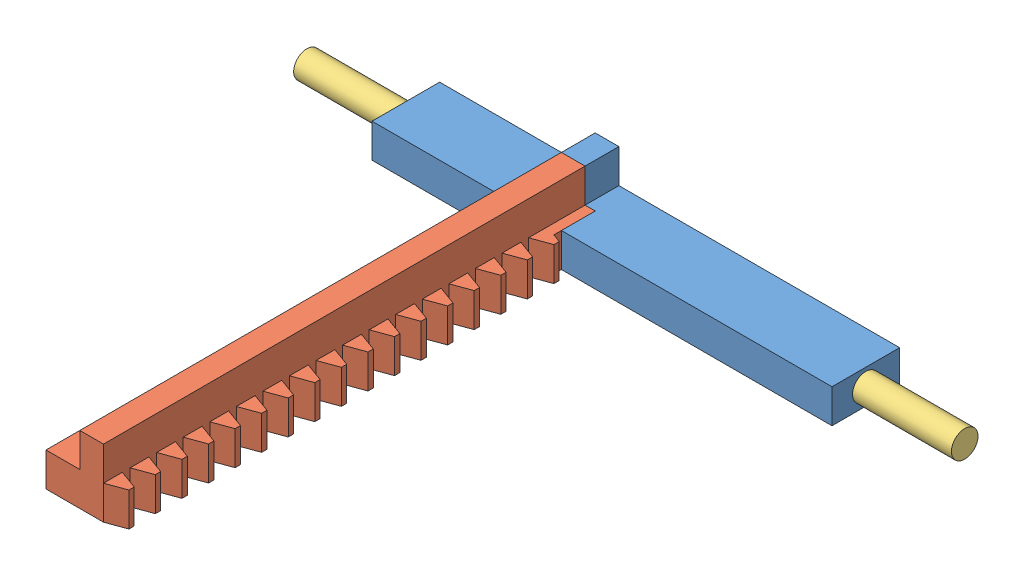
SolidWorks assembly payload-ejection-subscale-base-slider, configuration Default. Lengths in mm.
Overall size (61.75 6.47 48.38).
4 component instances, 3 part files, 5 mates.
Components (placement in the parent):
- payload-ejection-subscale-slider-sub1-1: payload-ejection-subscale-slider-sub1 [Default] at (21.2379 30.3357 47.517) size (45.72 6.35 6.35)
- payload-ejection-subscale-slider-subrack-1: payload-ejection-subscale-slider-subrack [Default] at (16.2227 29.3809 66.3819) x (0 0 1) z (0 1 0) size (45.2 7.14 6.35)
- payload-ejection-subscale-slider-subpin-1: payload-ejection-subscale-slider-subpin [Default] at (52.1129 30.3357 47.517) x (0 0.86352 -0.504314) z (-1 0 0) size (2.5 2.5 15)
- payload-ejection-subscale-slider-subpin-2: payload-ejection-subscale-slider-subpin [Default] at (-9.6371 30.3357 47.517) x (0 0 -1) z (1 0 0) size (2.5 2.5 15)
Mates (geometry in assembly coordinates):
- Coincident1: coincident anti-aligned: plane of payload-ejection-subscale-slider-sub1-1 through (21.2379 30.3357 47.517) normal (0 0 1); plane of payload-ejection-subscale-slider-subrack-1 through (16.2227 29.3809 47.517) normal (0 0 -1)
- Coincident2: coincident aligned: plane of payload-ejection-subscale-slider-sub1-1 through (21.2379 28.7482 47.517) normal (0 -1 0); plane of payload-ejection-subscale-slider-subrack-1 through (18.2217 28.7482 50.692) normal (0 -1 0)
- Coincident3: coincident anti-aligned: plane of payload-ejection-subscale-slider-sub1-1 through (11.0779 28.7482 47.517) normal (1 0 0); plane of payload-ejection-subscale-slider-subrack-1 through (11.0779 28.7482 50.692) normal (-1 0 0)
- Coincident4: coincident aligned: circle of payload-ejection-subscale-slider-sub1-1; circle of payload-ejection-subscale-slider-subpin-1
- Coincident5: coincident anti-aligned: circle of payload-ejection-subscale-slider-sub1-1; circle of payload-ejection-subscale-slider-subpin-2
